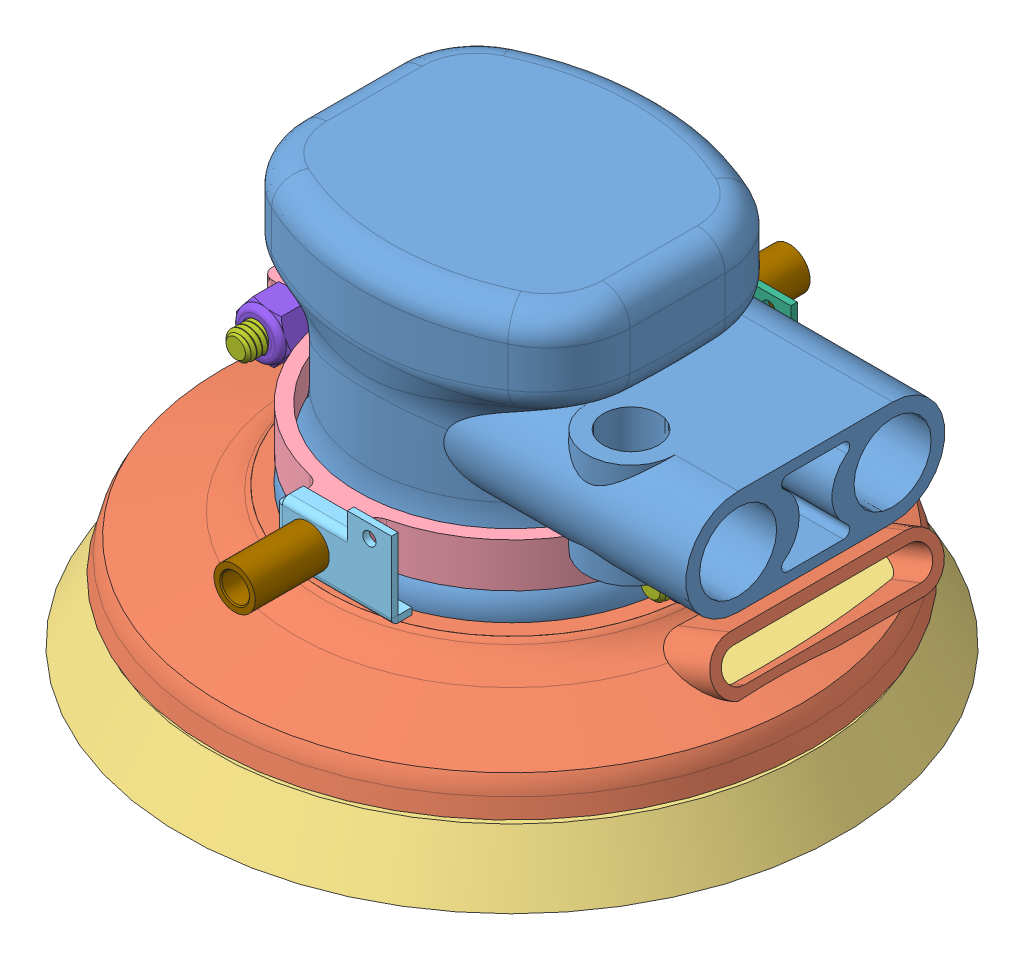
SolidWorks assembly Sander Captured, configuration Default. Lengths in mm.
Overall size (190.84 93.98 190.84).
14 component instances, 9 part files, 24 mates.
Components (placement in the parent):
- Sander Assembly-1: Sander Assembly [Default] at (-65.7268 -37.3375 -22.3736) size (190.84 93.98 190.84)
  - Body-1: Body [Default] at (13.4462 60.7349 53.9104) size (108.61 72.39 77.53)
  - Vacuum Shield-1: Vacuum Shield [Default] at (13.4462 8.6649 53.9104) x (0 0 1) z (-1 0 0) size (138.47 21.53 138.47)
  - Sanding Disk-1: Sanding Disk [Default] at (13.4462 -2.7651 53.9104) x (0.304446 0 0.95253) z (0 -1 0) size (151.82 151.82 22.86)
- Sander Strap (PT-1)-1: Sander Strap (PT-1) [Default] at (-52.2806 -14.7027 31.5368) size (109.22 10.16 45.21)
- Sander Strap (PT-1)-2: Sander Strap (PT-1) [Default] at (-52.2806 -14.7027 31.5368) x (-1 0 0) z (0 0 -1) size (109.22 10.16 45.21)
- Left Spring Hanger (PT-2)-1: Left Spring Hanger (PT-2) [Default] at (-48.682 -6.2043 78.2728) x (-1 0 0) z (0 0 1) size (26.7 18.06 4.7)
- Right Spring Hanger (PT-3)-1: Right Spring Hanger (PT-3) [Default] at (-47.567 -8.2344 -15.1992) x (-1 0 0) z (0 0 -1) size (26.7 18.06 4.7)
- Sander Strap Bolt (MMC 91251A540)-1: Sander Strap Bolt (MMC 91251A540) [91251A540] at (-100.0243 -9.6227 47.4118) size (9.53 9.53 26.14)
- Sander Strap Bolt (MMC 91251A540)-2: Sander Strap Bolt (MMC 91251A540) [91251A540] at (-4.5369 -9.6227 47.4118) size (9.53 9.53 26.14)
- Sander Strap Nylok (MMC 90630A110)-1: Sander Strap Nylok (MMC 90630A110) [90630A110] at (-4.5369 -9.6227 34.7118) x (1 0 0) z (0 -1 0) size (11.11 8.13 12.83)
- Sander Strap Nylok (MMC 90630A110)-2: Sander Strap Nylok (MMC 90630A110) [90630A110] at (-100.0243 -9.6227 34.7118) x (0.14483 0.989457 0) z (0.989457 -0.14483 0) size (11.11 8.13 12.83)
- Pitch Rod (PT-4)-1: Pitch Rod (PT-4) [Default] at (-52.2806 -9.6227 95.4178) x (-0.923728 -0.383049 0) z (0 0 -1) size (9.53 9.53 30.48)
- Pitch Rod (PT-4)-2: Pitch Rod (PT-4) [Default] at (-52.2806 -9.6227 -32.3442) size (9.53 9.53 30.48)
Mates (geometry in assembly coordinates):
- Concentric1: concentric aligned: circle of Sander Assembly-1/Body-1; circle of Sander Strap (PT-1)-1
- Coincident1: coincident aligned: circle of Sander Assembly-1/Body-1; plane of Sander Strap (PT-1)-1 through (-52.2806 -14.7027 31.5368) normal (0 -1 0)
- Concentric2: concentric aligned: circle of Sander Assembly-1/Body-1; circle of Sander Strap (PT-1)-2
- Coincident2: coincident aligned: circle of Sander Assembly-1/Body-1; plane of Sander Strap (PT-1)-2 through (-52.2806 -14.7027 31.5368) normal (0 -1 0)
- Coincident3: coincident anti-aligned: plane of Sander Strap (PT-1)-1 through (-106.8906 -4.5427 31.5368) normal (0 0 -1); plane of Sander Strap (PT-1)-2 through (-106.8906 -4.5427 31.5368) normal (0 0 1)
- Parallel1: parallel aligned: plane of Sander Assembly-1/Body-1 through (-90.3806 41.1773 20.5859) normal (-1 0 0); plane of Sander Strap (PT-1)-1 through (-58.6306 -14.7027 31.5358) normal (-1 0 0)
- Concentric6: concentric anti-aligned: cylinder of Sander Strap (PT-1)-1 through (-52.2806 -9.6227 72.9388) axis (0 0 1) radius 3.175; cylinder of Left Spring Hanger (PT-2)-1 through (-52.2806 -9.6227 78.2728) axis (0 0 -1) radius 3.175
- Parallel4: parallel aligned: plane of Sander Strap (PT-1)-1 through (-52.2806 -4.5427 31.5368) normal (0 1 0); plane of Left Spring Hanger (PT-2)-1 through (-48.682 -3.1203 78.2728) normal (0 1 0)
- Coincident14: coincident anti-aligned: plane of Sander Strap (PT-1)-1 through (-52.2806 -14.7027 76.7488) normal (0 0 1); plane of Left Spring Hanger (PT-2)-1 through (-48.682 -6.2043 76.7488) normal (0 0 -1)
- Concentric7: concentric anti-aligned: cylinder of Sander Strap (PT-1)-2 through (-52.2806 -9.6227 -9.8652) axis (0 0 -1) radius 3.175; cylinder of Right Spring Hanger (PT-3)-1 through (-52.2806 -9.6227 -15.1992) axis (0 0 1) radius 3.175
- Parallel5: parallel aligned: plane of Sander Strap (PT-1)-2 through (-52.2806 -4.5427 31.5368) normal (0 1 0); plane of Right Spring Hanger (PT-3)-1 through (-47.567 -3.1457 -15.1992) normal (0 1 0)
- Coincident16: coincident anti-aligned: plane of Sander Strap (PT-1)-2 through (-52.2806 -14.7027 -13.6752) normal (0 0 -1); plane of Right Spring Hanger (PT-3)-1 through (-47.567 -8.2344 -13.6752) normal (0 0 1)
- Concentric8: concentric anti-aligned: cylinder of Sander Strap (PT-1)-2 through (-100.0243 -9.6227 38.5218) axis (0 0 -1) radius 3.302; cylinder of Sander Strap Bolt (MMC 91251A540)-1 through (-100.0243 -9.6227 22.0118) axis (0 0 1) radius 4.7625
- Coincident17: coincident anti-aligned: plane of Sander Strap (PT-1)-2 through (-106.8906 -4.5427 28.3618) normal (0 0 -1); plane of Sander Strap Bolt (MMC 91251A540)-1 through (-100.0243 -9.6227 28.3618) normal (0 0 1)
- Concentric9: concentric anti-aligned: cylinder of Sander Strap (PT-1)-2 through (-4.5369 -9.6227 38.5218) axis (0 0 -1) radius 3.302; cylinder of Sander Strap Bolt (MMC 91251A540)-2 through (-4.5369 -9.6227 22.0118) axis (0 0 1) radius 4.7625
- Coincident18: coincident anti-aligned: plane of Sander Strap (PT-1)-2 through (2.3294 -4.5427 28.3618) normal (0 0 -1); plane of Sander Strap Bolt (MMC 91251A540)-2 through (-4.5369 -9.6227 28.3618) normal (0 0 1)
- Concentric10: concentric anti-aligned: cylinder of Sander Strap Bolt (MMC 91251A540)-2 through (-4.5369 -9.6227 22.0118) axis (0 0 1) radius 4.7625; cylinder of Sander Strap Nylok (MMC 90630A110)-1 through (-4.5369 -9.6227 41.4026) axis (0 0 -1) radius 2.6099
- Coincident19: coincident anti-aligned: plane of Sander Strap (PT-1)-1 through (2.3294 -4.5427 34.7118) normal (0 0 1); plane of Sander Strap Nylok (MMC 90630A110)-1 through (-4.5369 -3.2069 34.7118) normal (0 0 -1)
- Concentric11: concentric anti-aligned: cylinder of Sander Strap Bolt (MMC 91251A540)-1 through (-100.0243 -9.6227 22.0118) axis (0 0 1) radius 4.7625; cylinder of Sander Strap Nylok (MMC 90630A110)-2 through (-100.0243 -9.6227 41.4026) axis (0 0 -1) radius 2.6099
- Coincident20: coincident anti-aligned: plane of Sander Strap (PT-1)-1 through (-106.8906 -4.5427 34.7118) normal (0 0 1); plane of Sander Strap Nylok (MMC 90630A110)-2 through (-106.3725 -8.6935 34.7118) normal (0 0 -1)
- Concentric12: concentric: cylinder of Left Spring Hanger (PT-2)-1 through (-52.2806 -9.6227 78.2728) axis (0 0 -1) radius 3.175; cylinder of Pitch Rod (PT-4)-1 through (-52.2806 -9.6227 72.0498) axis (0 0 1) radius 3.175
- Distance1: distance = 0.127 mm anti-aligned: plane of Pitch Rod (PT-4)-1 through (-52.2806 -9.6227 78.3998) normal (0 0 -1); plane of Left Spring Hanger (PT-2)-1 through (-48.682 -6.2043 78.2728) normal (0 0 1)
- Concentric13: concentric: cylinder of Right Spring Hanger (PT-3)-1 through (-52.2806 -9.6227 -15.1992) axis (0 0 1) radius 3.175; cylinder of Pitch Rod (PT-4)-2 through (-52.2806 -9.6227 -8.9762) axis (0 0 -1) radius 3.175
- Distance2: distance = 0.127 mm anti-aligned: plane of Right Spring Hanger (PT-3)-1 through (-47.567 -8.2344 -15.1992) normal (0 0 -1); plane of Pitch Rod (PT-4)-2 through (-52.2806 -9.6227 -15.3262) normal (0 0 1)
